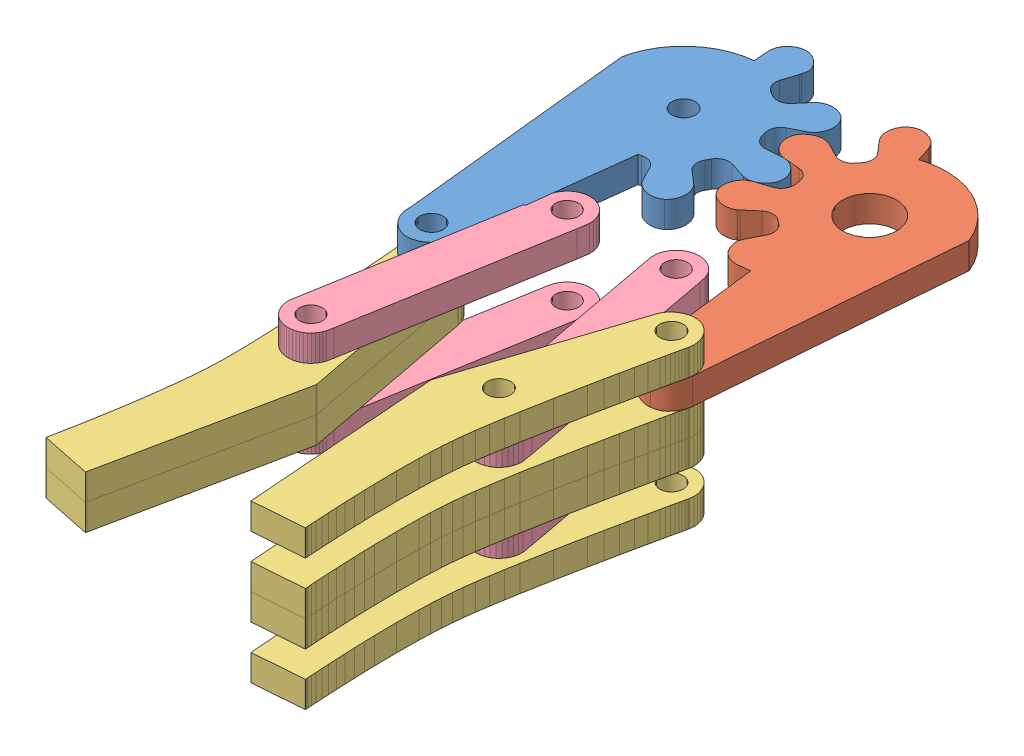
SolidWorks assembly fingers, configuration Default. Lengths in mm.
Overall size (54.79 21 94.68).
12 component instances, 4 part files, 7 mates.
Components (placement in the parent):
- gripper4-1: gripper4 [Default] at (24.988 22.41 5.8488) x (-0.992951 0 -0.118529) z (0 1 0) size (25.94 48.83 3.5)
- gripper5-1: gripper5 [Default] at (41.3128 22.41 3.8433) x (-0.992823 0 0.119595) z (0 1 0) size (24.04 47.84 3.5)
- gripper3-1: gripper3 [Default] at (18.909 18.91 46.6317) x (-0.97912 0 -0.203285) z (0 1 0) size (15.08 50 3.5)
- gripper1-1: gripper1 [Default] at (3.7805 25.91 70.0393) x (0.169533 0 -0.985524) z (0 -1 0) size (35.69 6.12 3.5)
- gripper3-4: gripper3 [Default] at (23.0641 29.41 44.8122) x (0.997138 0 -0.075609) z (0 -1 0) size (15.08 50 3.5)
- gripper1-3: gripper1 [Default] at (22.8652 22.41 35.5142) x (0.184074 0 0.982912) z (0 1 0) size (35.69 6.12 3.5)
- gripper3-5: gripper3 [Default] at (23.0641 22.41 44.8122) x (0.997138 0 -0.075609) z (0 -1 0) size (15.08 50 3.5)
- gripper3-6: gripper3 [Default] at (23.0641 18.91 44.8122) x (0.997138 0 -0.075609) z (0 -1 0) size (15.08 50 3.5)
- gripper3-7: gripper3 [Default] at (18.909 15.41 46.6317) x (-0.97912 0 -0.203285) z (0 1 0) size (15.08 50 3.5)
- gripper1-4: gripper1 [Default] at (22.8652 11.91 35.5142) x (0.184074 0 0.982912) z (0 1 0) size (35.69 6.12 3.5)
- gripper1-5: gripper1 [Default] at (3.7805 15.41 70.0393) x (0.169533 0 -0.985524) z (0 -1 0) size (35.69 6.12 3.5)
- gripper3-8: gripper3 [Default] at (23.0641 11.91 44.8122) x (0.997138 0 -0.075609) z (0 -1 0) size (15.08 50 3.5)
Mates (geometry in assembly coordinates):
- Coincident4: coincident anti-aligned: plane of gripper4-1 through (9.5013 22.41 25.5635) normal (0 -1 0); plane of gripper3-1 through (5.923 22.41 72.028) normal (0 1 0)
- Concentric3: concentric aligned: cylinder of gripper4-1 through (4.7901 22.41 48.9437) axis (0 1 0) radius 1.563; cylinder of gripper3-1 through (4.7901 18.91 48.9437) axis (0 1 0) radius 1.563
- Concentric5: concentric anti-aligned: cylinder of gripper3-1 through (7.3109 18.91 67.5408) axis (0 1 0) radius 1.5595; cylinder of gripper1-1 through (7.3109 25.91 67.5408) axis (0 -1 0) radius 1.53
- Coincident6: coincident anti-aligned: plane of gripper5-1 through (31.9048 25.91 26.22) normal (0 1 0); plane of gripper3-4 through (32.6743 25.91 71.6683) normal (0 -1 0)
- Concentric6: concentric anti-aligned: cylinder of gripper5-1 through (36.7681 22.41 48.9217) axis (0 1 0) radius 1.5635; cylinder of gripper3-4 through (36.7681 29.41 48.9217) axis (0 -1 0) radius 1.563
- Concentric8: concentric anti-aligned: cylinder of gripper3-4 through (31.8753 29.41 67.0399) axis (0 -1 0) radius 1.5595; cylinder of gripper1-3 through (31.8753 22.41 67.0399) axis (0 1 0) radius 1.53
- GearMate1: gear = 25.4 : 25.4 mm: cylinder of gripper5-1 through (33.1544 22.41 18.8749) axis (0 1 0) radius 3.601; cylinder of gripper4-1 through (8.376 22.41 18.9026) axis (0 1 0) radius 1.563
